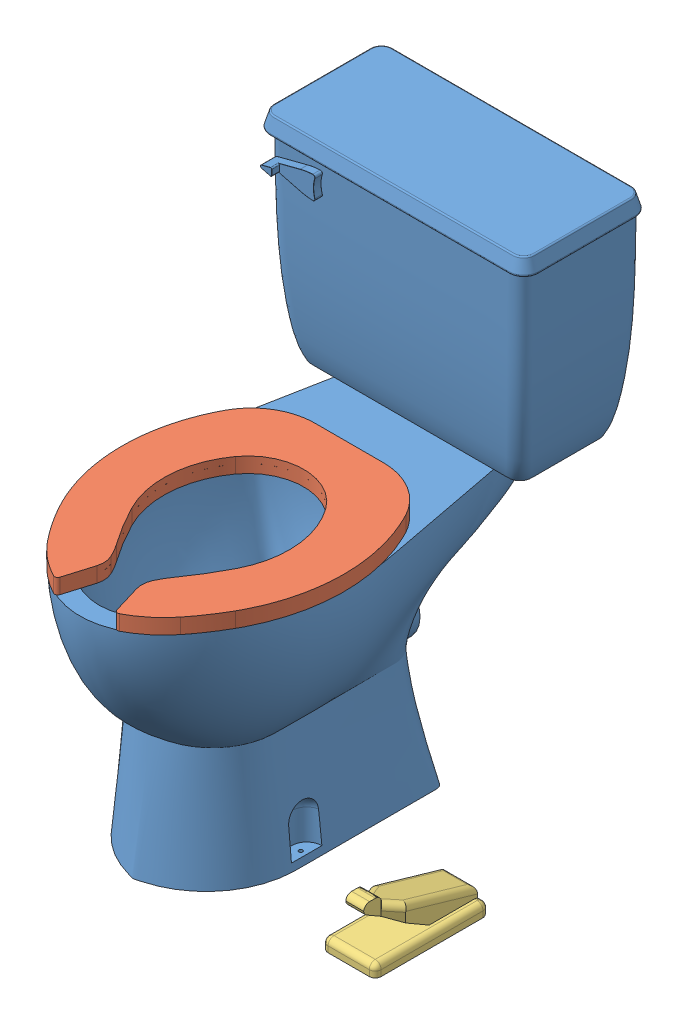
SolidWorks assembly Toilet_Assm, configuration Detailed Right Side. Lengths in mm.
Overall size (687.24 878.83 853.08).
5 component instances, 4 part files, 14 mates.
Components (placement in the parent):
- Toilet-1: Toilet [Detailed] at origin size (675.99 878.83 842.38)
- Toilet Seat-1: Toilet Seat [Detailed Model] at (0 0 149.225) x (-1 0 0) z (0 0 -1) size (416.1 44.59 483.9)
- FootFlush-1: FootFlush [Default] at (-349.25 -425.45 480.3601) (suppressed, hidden)
- FootFlush-2: FootFlush [Default] at (260.35 -425.45 480.3601)
- FlushMinder-1: FlushMinder [Default] at (-38.1 387.35 -104.775) (suppressed, hidden)
Mates (geometry in assembly coordinates):
- Coincident1: coincident anti-aligned: plane of Toilet-1 through (0 0 0) normal (0 1 0); plane of Toilet Seat-1 through (0 0 149.225) normal (0 -1 0)
- Coincident2: coincident anti-aligned: plane of Toilet-1 through (0 0 0) normal (1 0 0); plane of Toilet Seat-1 through (0 0 149.225) normal (-1 0 0)
- Coincident3: coincident anti-aligned: line of Toilet-1 through (-69.85 0 149.225) axis (1 0 0); line of Toilet Seat-1 through (69.85 0 149.225) axis (-1 0 0)
- Coincident4: coincident aligned: plane of FootFlush-1 through (-349.25 -425.45 480.3601) normal (0 1 0)
- Parallel1: parallel aligned: plane of FootFlush-1 through (-349.25 -425.45 480.3601) normal (1 0 0)
- Distance1: distance = 25.4 mm: plane of FootFlush-1 through (-349.25 -425.45 289.8601) normal (0 0 1)
- Distance2: distance = 63.5 mm: plane of FootFlush-1 through (-304.8 -425.45 480.3601) normal (1 0 0)
- Coincident7: coincident aligned: plane of FootFlush-2 through (260.35 -425.45 480.3601) normal (0 1 0)
- Parallel2: parallel aligned: plane of FootFlush-2 through (260.35 -425.45 480.3601) normal (1 0 0)
- Distance3: distance = 25.4 mm: plane of FootFlush-2 through (260.35 -425.45 289.8601) normal (0 0 1)
- Distance4: distance = 63.5 mm: plane of FootFlush-2 through (304.8 -425.45 480.3601) normal (1 0 0)
- Coincident8: coincident: plane of Toilet-1 through (0 0 -104.775) normal (0 0 1); plane of FlushMinder-1 through (-38.1 387.35 -104.775) normal (0 0 -1)
- Distance5: distance = 38.1 mm: plane of Toilet-1 through (0 0 0) normal (1 0 0); plane of FlushMinder-1 through (-38.1 387.35 -104.775) normal (1 0 0)
- Distance6: distance = 812.8 mm: plane of assembly through (0 -425.45 0) normal (0 1 0); plane of assembly; plane of FlushMinder-1 through (-38.1 387.35 -104.775) normal (0 1 0)
